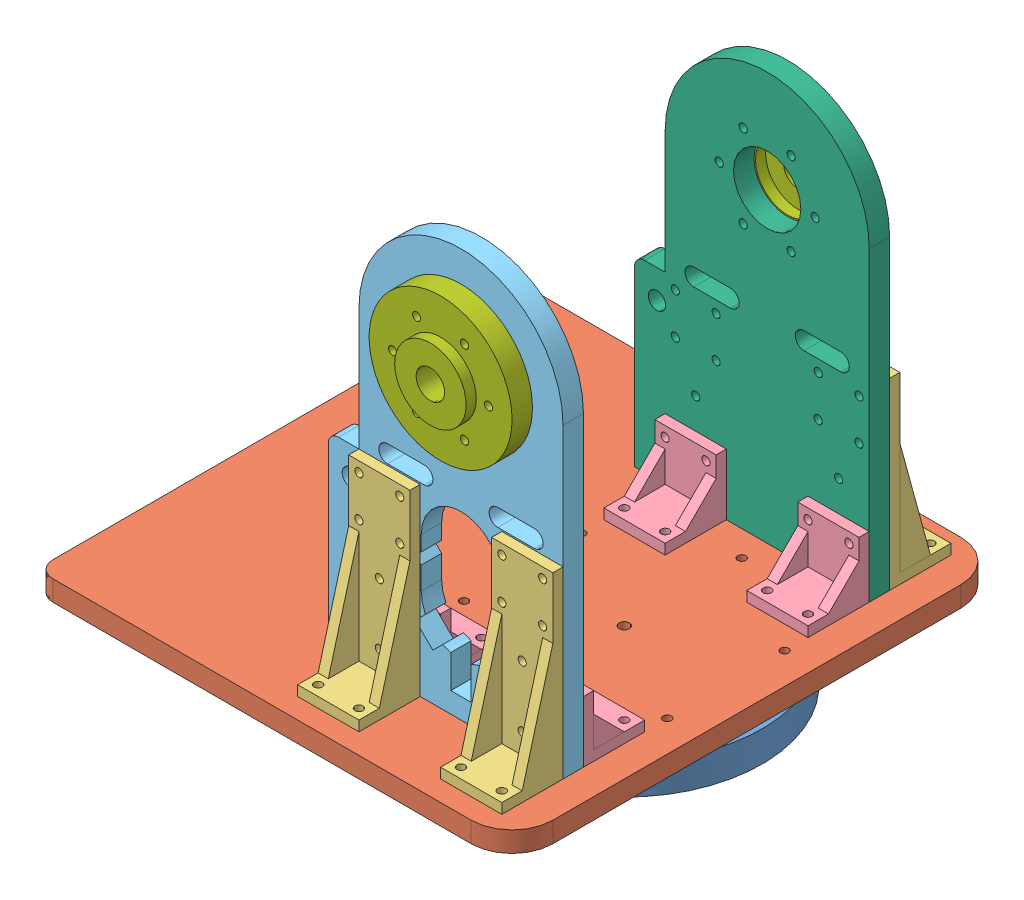
SolidWorks assembly khau1, configuration Default. Lengths in mm.
Overall size (235.5 225 240).
14 component instances, 7 part files, 39 mates.
Components (placement in the parent):
- de duoi-2: de duoi [Default] at (37.109 75.6339 112.207) x (-1 0 0) z (0 0 1) size (135 15 135)
- dev2-1: dev2 [Default] at (37.109 75.6339 112.207) size (233 10 240)
- ke lon-1: ke lon [Default] at (72.109 85.6339 207.207) x (0 0 1) z (-1 0 0) size (30 90 30)
- ke lon-2: ke lon [Default] at (2.109 85.6339 207.207) x (0 0 1) z (-1 0 0) size (30 90 30)
- ke lon-3: ke lon [Default] at (72.109 85.6339 17.207) x (0 0 -1) z (1 0 0) size (30 90 30)
- ke lon-4: ke lon [Default] at (2.109 85.6339 17.207) x (0 0 -1) z (1 0 0) size (30 90 30)
- ke nho-1: ke nho [Default] at (72.109 85.6339 167.207) x (0 0 -1) z (1 0 0) size (30 30 30)
- ke nho-2: ke nho [Default] at (2.109 85.6339 167.207) x (0 0 -1) z (1 0 0) size (30 30 30)
- ke nho-3: ke nho [Default] at (72.109 85.6339 57.207) x (0 0 1) z (-1 0 0) size (30 30 30)
- ke nho-4: ke nho [Default] at (2.109 85.6339 57.207) x (0 0 1) z (-1 0 0) size (30 30 30)
- khau1_phai-1: khau1_phai [Default] at (39.4354 227.5146 182.207) x (1 0 0) z (0 -1 0) size (115 10 200)
- khau1_trai-1: khau1_trai [Default] at (39.4354 227.5146 32.207) x (1 0 0) z (0 -1 0) size (115 10 200)
- dem co dinh v2-1: dem co dinh v2 [Default] at (37.109 235.6339 32.207) x (0.866025 0.5 0) z (-0.5 0.866025 0) size (70 15 70)
- dem co dinh v2-2: dem co dinh v2 [Default] at (37.109 235.6339 192.207) x (0 -1 0) z (-1 0 0) size (70 15 70)
Mates (geometry in assembly coordinates):
- Concentric1: concentric: cylinder of assembly; cylinder of assembly; cylinder of de duoi-2 through (37.109 80.6339 112.207) axis (0 -1 0) radius 2.5; cylinder of dev2-1 through (37.109 85.6339 112.207) axis (0 -1 0) radius 2.5
- Concentric2: concentric: cylinder of assembly; cylinder of assembly; cylinder of de duoi-2 through (37.109 75.6339 54.707) axis (0 -1 0) radius 2; cylinder of dev2-1 through (37.109 85.6339 54.707) axis (0 -1 0) radius 2
- Concentric3: concentric: cylinder of assembly; cylinder of assembly; cylinder of dev2-1 through (82.109 85.6339 217.207) axis (0 -1 0) radius 2; cylinder of ke lon-1 through (82.109 85.6339 217.207) axis (0 1 0) radius 2
- Concentric4: concentric: cylinder of assembly; cylinder of assembly; cylinder of dev2-1 through (62.109 85.6339 217.207) axis (0 -1 0) radius 2; cylinder of ke lon-1 through (62.109 85.6339 217.207) axis (0 1 0) radius 2
- Coincident2: coincident: plane of assembly; plane of assembly; plane of dev2-1 through (-155.891 85.6339 12.207) normal (0 1 0); plane of ke lon-1 through (72.109 85.6339 207.207) normal (0 -1 0)
- Concentric5: concentric: cylinder of assembly; cylinder of assembly; cylinder of dev2-1 through (-7.891 85.6339 217.207) axis (0 -1 0) radius 2; cylinder of ke lon-2 through (-7.891 85.6339 217.207) axis (0 1 0) radius 2
- Concentric6: concentric: cylinder of assembly; cylinder of assembly; cylinder of dev2-1 through (12.109 85.6339 217.207) axis (0 -1 0) radius 2; cylinder of ke lon-2 through (12.109 85.6339 217.207) axis (0 1 0) radius 2
- Coincident3: coincident: plane of assembly; plane of assembly; plane of dev2-1 through (-155.891 85.6339 12.207) normal (0 1 0); plane of ke lon-2 through (2.109 85.6339 207.207) normal (0 -1 0)
- Concentric7: concentric: cylinder of assembly; cylinder of assembly; cylinder of dev2-1 through (62.109 85.6339 7.207) axis (0 -1 0) radius 2; cylinder of ke lon-3 through (62.109 85.6339 7.207) axis (0 1 0) radius 2
- Concentric8: concentric: cylinder of assembly; cylinder of assembly; cylinder of dev2-1 through (82.109 85.6339 7.207) axis (0 -1 0) radius 2; cylinder of ke lon-3 through (82.109 85.6339 7.207) axis (0 1 0) radius 2
- Coincident4: coincident: plane of assembly; plane of assembly; plane of dev2-1 through (-155.891 85.6339 12.207) normal (0 1 0); plane of ke lon-3 through (72.109 85.6339 17.207) normal (0 -1 0)
- Concentric9: concentric: cylinder of assembly; cylinder of assembly; cylinder of dev2-1 through (12.109 85.6339 7.207) axis (0 -1 0) radius 2; cylinder of ke lon-4 through (12.109 85.6339 7.207) axis (0 1 0) radius 2
- Concentric10: concentric: cylinder of assembly; cylinder of assembly; cylinder of dev2-1 through (-7.891 85.6339 7.207) axis (0 -1 0) radius 2; cylinder of ke lon-4 through (-7.891 85.6339 7.207) axis (0 1 0) radius 2
- Coincident5: coincident: plane of assembly; plane of assembly; plane of dev2-1 through (-155.891 85.6339 12.207) normal (0 1 0); plane of ke lon-4 through (2.109 85.6339 17.207) normal (0 -1 0)
- Concentric11: concentric: cylinder of assembly; cylinder of assembly; cylinder of dev2-1 through (62.109 85.6339 157.207) axis (0 -1 0) radius 2; cylinder of ke nho-1 through (62.109 85.6339 157.207) axis (0 1 0) radius 2
- Concentric12: concentric: cylinder of assembly; cylinder of assembly; cylinder of dev2-1 through (82.109 85.6339 157.207) axis (0 -1 0) radius 2; cylinder of ke nho-1 through (82.109 85.6339 157.207) axis (0 1 0) radius 2
- Coincident6: coincident: plane of assembly; plane of assembly; plane of dev2-1 through (-155.891 85.6339 12.207) normal (0 1 0); plane of ke nho-1 through (72.109 85.6339 167.207) normal (0 -1 0)
- Concentric13: concentric: cylinder of assembly; cylinder of assembly; cylinder of dev2-1 through (-7.891 85.6339 157.207) axis (0 -1 0) radius 2; cylinder of ke nho-2 through (-7.891 85.6339 157.207) axis (0 1 0) radius 2
- Concentric14: concentric: cylinder of assembly; cylinder of assembly; cylinder of dev2-1 through (12.109 85.6339 157.207) axis (0 -1 0) radius 2; cylinder of ke nho-2 through (12.109 85.6339 157.207) axis (0 1 0) radius 2
- Coincident7: coincident: plane of assembly; plane of assembly; plane of dev2-1 through (-155.891 85.6339 12.207) normal (0 1 0); plane of ke nho-2 through (2.109 85.6339 167.207) normal (0 -1 0)
- Coincident8: coincident: plane of assembly; plane of assembly; plane of dev2-1 through (-155.891 85.6339 12.207) normal (0 1 0); plane of ke nho-3 through (72.109 85.6339 57.207) normal (0 -1 0)
- Concentric15: concentric: cylinder of assembly; cylinder of assembly; cylinder of dev2-1 through (82.109 85.6339 67.207) axis (0 -1 0) radius 2; cylinder of ke nho-3 through (82.109 85.6339 67.207) axis (0 1 0) radius 2
- Concentric16: concentric: cylinder of assembly; cylinder of assembly; cylinder of dev2-1 through (62.109 85.6339 67.207) axis (0 -1 0) radius 2; cylinder of ke nho-3 through (62.109 85.6339 67.207) axis (0 1 0) radius 2
- Concentric17: concentric: cylinder of assembly; cylinder of assembly; cylinder of dev2-1 through (12.109 85.6339 67.207) axis (0 -1 0) radius 2; cylinder of ke nho-4 through (12.109 85.6339 67.207) axis (0 1 0) radius 2
- Concentric18: concentric: cylinder of assembly; cylinder of assembly; cylinder of dev2-1 through (-7.891 85.6339 67.207) axis (0 -1 0) radius 2; cylinder of ke nho-4 through (-7.891 85.6339 67.207) axis (0 1 0) radius 2
- Coincident9: coincident: plane of assembly; plane of assembly; plane of dev2-1 through (-155.891 85.6339 12.207) normal (0 1 0); plane of ke nho-4 through (2.109 85.6339 57.207) normal (0 -1 0)
- Coincident10: coincident: plane of assembly; plane of assembly; plane of ke lon-1 through (87.109 90.6339 192.207) normal (1 0 0); plane of khau1_phai-1 through (87.109 227.5146 192.207) normal (1 0 0)
- Coincident11: coincident: plane of assembly; plane of assembly; plane of dev2-1 through (-155.891 85.6339 12.207) normal (0 1 0); plane of khau1_phai-1 through (39.4354 85.6339 192.207) normal (0 -1 0)
- Coincident12: coincident: plane of assembly; plane of assembly; plane of ke lon-2 through (-12.891 90.6339 192.207) normal (0 0 -1); plane of khau1_phai-1 through (39.4354 227.5146 192.207) normal (0 0 1)
- Coincident13: coincident: plane of assembly; plane of assembly; plane of ke lon-3 through (87.109 90.6339 32.207) normal (1 0 0); plane of khau1_trai-1 through (87.109 227.5146 42.207) normal (1 0 0)
- Coincident14: coincident: plane of assembly; plane of assembly; plane of dev2-1 through (-155.891 85.6339 12.207) normal (0 1 0); plane of khau1_trai-1 through (39.4354 85.6339 42.207) normal (0 -1 0)
- Coincident15: coincident: plane of assembly; plane of assembly; plane of ke nho-3 through (57.109 90.6339 42.207) normal (0 0 -1); plane of khau1_trai-1 through (39.4354 227.5146 42.207) normal (0 0 1)
- Coincident16: coincident: plane of assembly; plane of assembly; plane of de duoi-2 through (37.109 75.6339 112.207) normal (0 1 0); plane of dev2-1 through (-155.891 75.6339 12.207) normal (0 -1 0)
- Concentric19: concentric: cylinder of assembly; cylinder of assembly; cylinder of khau1_trai-1 through (37.109 235.6339 42.207) axis (0 0 -1) radius 16.5; cylinder of dem co dinh v2-1 through (37.109 235.6339 17.207) axis (0 0 1) radius 7
- Concentric20: concentric: cylinder of assembly; cylinder of assembly; cylinder of khau1_phai-1 through (37.109 235.6339 192.207) axis (0 0 -1) radius 16.5; cylinder of dem co dinh v2-2 through (37.109 235.6339 207.207) axis (0 0 -1) radius 7
- Concentric21: concentric: cylinder of assembly; cylinder of assembly; cylinder of khau1_trai-1 through (25.359 255.9855 42.207) axis (0 0 -1) radius 2; cylinder of dem co dinh v2-1 through (25.359 255.9855 27.207) axis (0 0 1) radius 5
- Concentric22: concentric: cylinder of assembly; cylinder of assembly; cylinder of khau1_phai-1 through (25.359 255.9855 192.207) axis (0 0 -1) radius 2; cylinder of dem co dinh v2-2 through (25.359 255.9855 192.207) axis (0 0 1) radius 2
- Coincident17: coincident: plane of assembly; plane of assembly; plane of khau1_phai-1 through (39.4354 227.5146 192.207) normal (0 0 1); plane of dem co dinh v2-2 through (37.109 235.6339 192.207) normal (0 0 -1)
- Coincident18: coincident: plane of assembly; plane of assembly; plane of khau1_trai-1 through (39.4354 227.5146 32.207) normal (0 0 -1); plane of dem co dinh v2-1 through (37.109 235.6339 32.207) normal (0 0 1)
